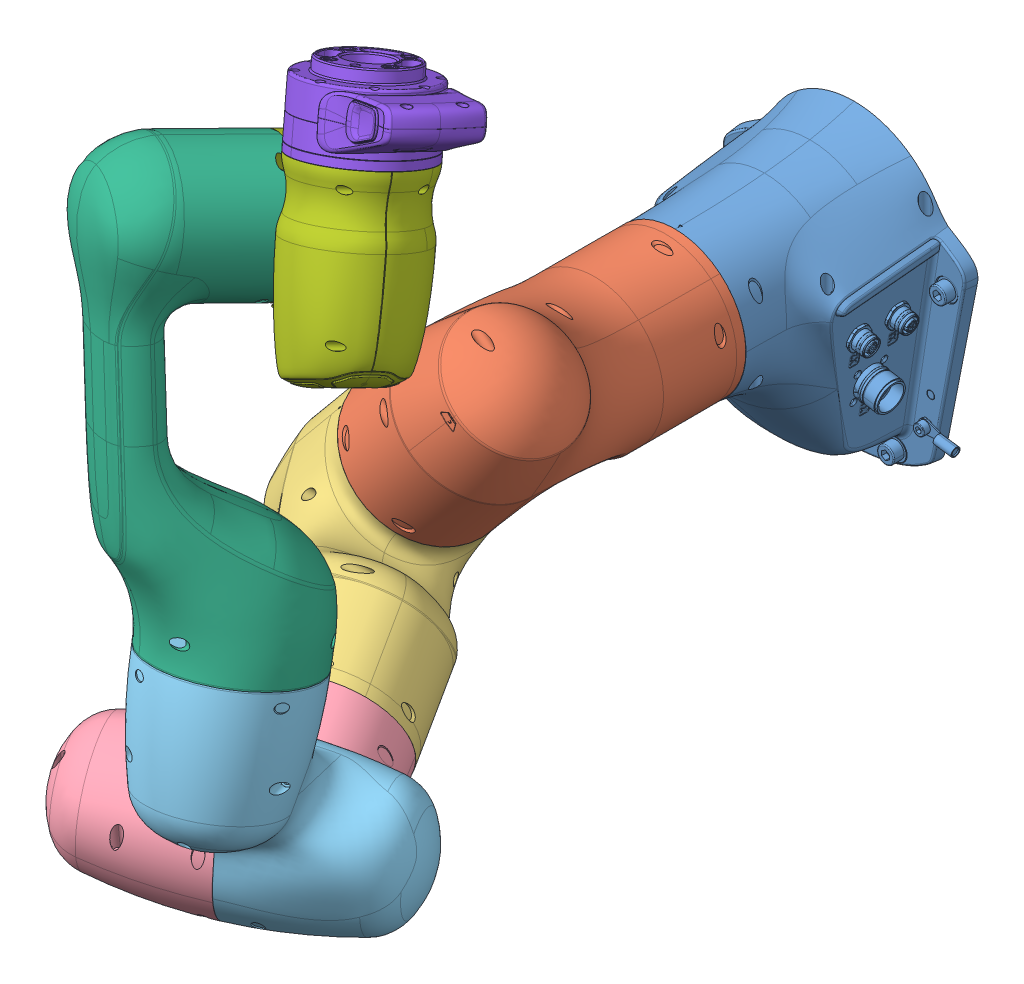
SolidWorks assembly __ARM, configuration Default. Lengths in mm.
Overall size (561.45 860.47 1072.19).
8 component instances, 8 part files, 14 mates.
Components (placement in the parent):
- BA_J1_adapted_Standard-1: BA_J1_adapted_Standard [Default] at origin size (190.39 246.49 162.25)
- SH_J1J2_adapted_Standard-1: SH_J1J2_adapted_Standard [Default] at (-0.1106 0.2631 332) x (-0.771742 0.635936 0) z (0.635936 0.771742 0) size (115.32 251.62 199.65)
- SH_J2J3_adapted_Standard-1: SH_J2J3_adapted_Standard [Default] at (0.5254 1.0347 332.0006) x (-0.650813 0.536288 0.537436) z (-0.635936 -0.771742 0) size (115.32 254.62 199.65)
- EL_J3J4_adapted_Standard-1: EL_J3J4_adapted_Standard [Default] at (80.1199 -64.3609 494.0852) x (0.887714 -0.051558 -0.457499) z (0.414762 -0.341775 0.843305) size (168.02 294.04 179.56)
- EL_J4J5_adapted_Standard-1: EL_J4J5_adapted_Standard [Default] at (172.9733 112.5328 656.5052) x (-0.887714 0.051558 0.457499) z (0.089462 -0.955452 0.281263) size (168.02 294.05 184.56)
- LA_J5J6_adapted_Standard-1: LA_J5J6_adapted_Standard [Default] at (173.0419 112.6276 656.6277) x (-0.90089 -0.19805 -0.386229) z (-0.089462 0.955452 -0.281263) size (162.89 590.44 450.77)
- WR_J6_adapted_Standard-1: WR_J6_adapted_Standard [Default] at (226.1636 392.655 613.6925) x (0.872801 0.356719 0.333123) z (0.424728 -0.218835 -0.878475) size (211.94 250.58 301.08)
- WR_J7_adapted_Standard-1: WR_J7_adapted_Standard [Default] at (226.404 391.7468 614.035) x (0.395072 0.41389 0.82013) z (0.886619 0.061901 -0.45834) size (143.77 54.81 143.77)
Mates (geometry in assembly coordinates):
- Coincidente1: coincident anti-aligned: line of BA_J1_adapted_Standard-1 through (0.0001 0.158 140) axis (0 0 1); line of SH_J1J2_adapted_Standard-1 through (0.0001 0.158 140) axis (0 0 -1)
- Coincidente2: coincident anti-aligned: plane of BA_J1_adapted_Standard-1 through (57 76.608 140) normal (0 0 1); plane of SH_J1J2_adapted_Standard-1 through (82.8207 9.6717 140) normal (0 0 -1)
- Coincidente3: coincident anti-aligned: line of SH_J1J2_adapted_Standard-1 through (0.2073 0.649 332.0003) axis (-0.635936 -0.771742 0); line of SH_J2J3_adapted_Standard-1 through (0.2073 0.649 332.0003) axis (0.635936 0.771742 0)
- Coincidente4: coincident anti-aligned: plane of SH_J1J2_adapted_Standard-1 through (44.9825 -36.247 392) normal (-0.635936 -0.771742 0); plane of SH_J2J3_adapted_Standard-1 through (13.0809 -9.9592 250.2212) normal (0.635936 0.771742 0)
- Coincidente5: coincident anti-aligned: line of SH_J2J3_adapted_Standard-1 through (80.8963 -65.1792 495.684) axis (0.414762 -0.341775 0.843305); line of EL_J3J4_adapted_Standard-1 through (80.8963 -65.1792 495.684) axis (-0.414762 0.341775 -0.843305)
- Coincidente6: coincident anti-aligned: plane of SH_J2J3_adapted_Standard-1 through (80.9892 -65.2696 495.6017) normal (0.414762 -0.341775 0.843305); plane of EL_J3J4_adapted_Standard-1 through (-3.602 -208.7541 479.0546) normal (-0.414762 0.341775 -0.843305)
- Coincidente7: coincident anti-aligned: line of EL_J3J4_adapted_Standard-1 through (147.1578 -28.9411 621.2644) axis (0.887714 -0.051558 -0.457499); line of EL_J4J5_adapted_Standard-1 through (147.1578 -28.9411 621.2644) axis (-0.887714 0.051558 0.457499)
- Coincidente8: coincident anti-aligned: plane of EL_J3J4_adapted_Standard-1 through (79.676 -64.3351 494.314) normal (0.887714 -0.051558 -0.457499); plane of EL_J4J5_adapted_Standard-1 through (173.4171 112.507 656.2764) normal (-0.887714 0.051558 0.457499)
- Coincidente9: coincident anti-aligned: line of EL_J4J5_adapted_Standard-1 through (172.9524 113.583 656.3464) axis (-0.089462 0.955452 -0.281263); line of LA_J5J6_adapted_Standard-1 through (170.7152 137.4764 649.3127) axis (0.089462 -0.955452 0.281263)
- Coincidente10: coincident anti-aligned: plane of EL_J4J5_adapted_Standard-1 through (172.8793 113.536 656.2099) normal (-0.089462 0.955452 -0.281263); plane of LA_J5J6_adapted_Standard-1 through (172.9524 113.583 656.3464) normal (0.089462 -0.955452 0.281263)
- Coincidente11: coincident anti-aligned: line of LA_J5J6_adapted_Standard-1 through (134.5766 368.8792 614.9486) axis (0.424728 -0.218835 -0.878475); line of WR_J6_adapted_Standard-1 through (150.9286 360.4541 581.1273) axis (-0.424728 0.218835 0.878475)
- Coincidente13: coincident anti-aligned: plane of LA_J5J6_adapted_Standard-1 through (166.3312 116.0852 670.5076) normal (0.424728 -0.218835 -0.878475); plane of WR_J6_adapted_Standard-1 through (143.0712 364.5025 597.3791) normal (-0.424728 0.218835 0.878475)
- Coincidente14: coincident aligned: line of WR_J6_adapted_Standard-1 through (213.8515 439.1559 596.1561) axis (0.240469 -0.90822 0.342507); line of WR_J7_adapted_Standard-1 through (203.3178 478.9405 581.1526) axis (0.240469 -0.90822 0.342507)
- Coincidente15: coincident anti-aligned: plane of WR_J6_adapted_Standard-1 through (182.4307 426.314 584.1637) normal (-0.240469 0.90822 -0.342507); plane of WR_J7_adapted_Standard-1 through (213.8515 439.1559 596.1561) normal (0.240469 -0.90822 0.342507)
